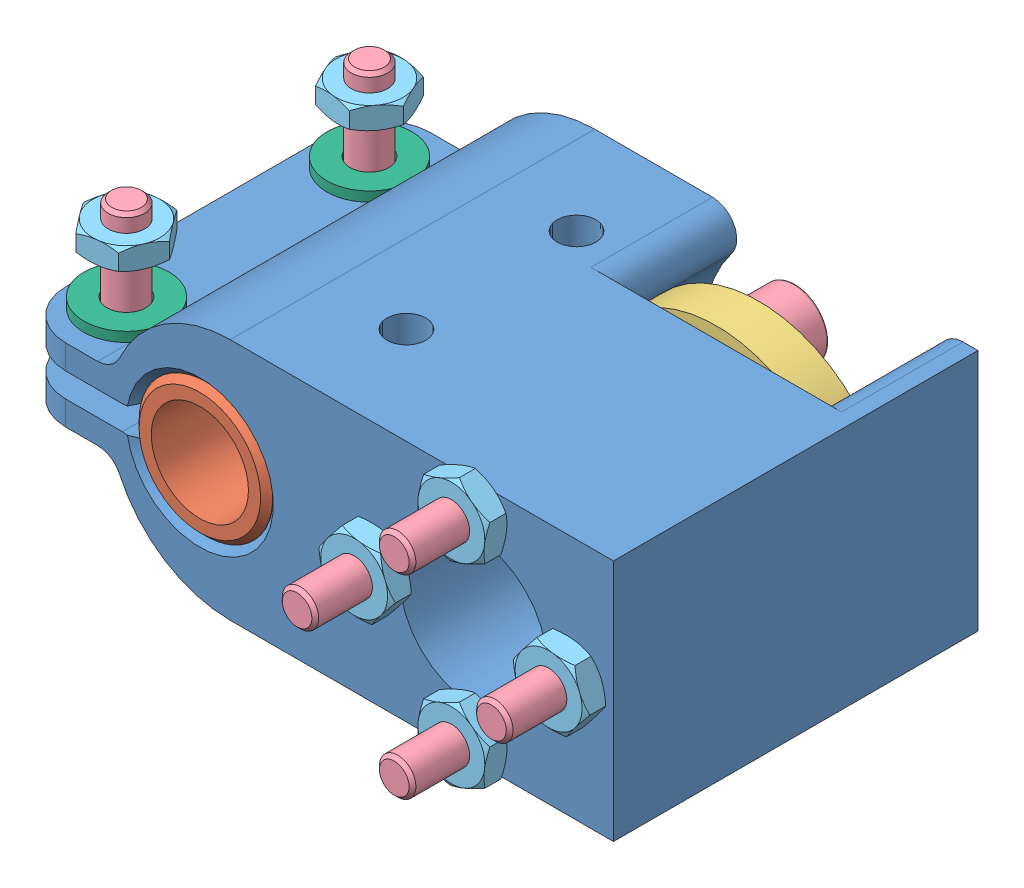
SolidWorks assembly X CHARIOT ASSY, configuration Default. Lengths in mm.
Overall size (49.4 23.51 36.69).
17 component instances, 6 part files, 17 mates.
Components (placement in the parent):
- lead x chariot-1: lead x chariot [Default] at (13.8207 -0.0483 62.5173) size (49.08 20 30.38)
- brass sleeve 30mm-2: brass sleeve 30mm [Default] at (-8.6793 -0.0483 62.5173) x (0.987351 0.158553 0) z (0 0 1) size (11 11 30)
- LeadScrew Nut 8mm x 2mmPitch (1)-1: LeadScrew Nut 8mm x 2mmPitch (1) [Default] at (13.8207 -0.0483 69.0173) x (-1 0 0) z (0 0 -1) size (22 22 16.05)
- socket head cap screw_iso2-2: socket head cap screw_iso2 [ISO 4762 M3 x 30 - 18N] at (5.8207 -0.0483 66.0173) x (0 0 1) z (0.923728 0.383049 0) size (33 5.5 5.5)
- socket head cap screw_iso2-3: socket head cap screw_iso2 [ISO 4762 M3 x 30 - 18N] at (13.8207 7.9517 66.0173) x (0 0 1) z (0.383049 -0.923728 0) size (33 5.5 5.5)
- socket head cap screw_iso2-4: socket head cap screw_iso2 [ISO 4762 M3 x 30 - 18N] at (21.8207 -0.0483 66.0173) x (0 0 1) z (-0.923728 -0.383049 0) size (33 5.5 5.5)
- socket head cap screw_iso2-5: socket head cap screw_iso2 [ISO 4762 M3 x 30 - 18N] at (13.8207 -8.0483 66.0173) x (0 0 1) z (-0.383049 0.923728 0) size (33 5.5 5.5)
- hex thin nut chamfered gradeab_iso-1: hex thin nut chamfered gradeab_iso [ISO - 4035 - M3 - N] at (21.8207 -0.0483 92.5173) x (-0.923728 -0.383049 0) z (0 0 -1) size (5.5 6.35 1.8)
- hex thin nut chamfered gradeab_iso-2: hex thin nut chamfered gradeab_iso [ISO - 4035 - M3 - N] at (13.8207 -8.0483 92.5173) x (-0.383049 0.923728 0) z (0 0 -1) size (5.5 6.35 1.8)
- hex thin nut chamfered gradeab_iso-3: hex thin nut chamfered gradeab_iso [ISO - 4035 - M3 - N] at (5.8207 -0.0483 92.5173) x (0.923728 0.383049 0) z (0 0 -1) size (5.5 6.35 1.8)
- hex thin nut chamfered gradeab_iso-4: hex thin nut chamfered gradeab_iso [ISO - 4035 - M3 - N] at (13.8207 7.9517 92.5173) x (0.383049 -0.923728 0) z (0 0 -1) size (5.5 6.35 1.8)
- socket head cap screw_iso2-8: socket head cap screw_iso2 [ISO 4762 M3 x 10 - 10N] at (-19.7187 -2.2811 67.5173) x (0 1 0) z (0.395734 0 0.918365) size (13 5.5 5.5)
- socket head cap screw_iso2-9: socket head cap screw_iso2 [ISO 4762 M3 x 10 - 10N] at (-19.7187 -2.2811 87.5173) x (0 1 0) z (0.6 0 0.8) size (13 5.5 5.5)
- plain washer 10673 type snl_iso-3: plain washer 10673 type snl_iso [ISO 10673-3.2-S] at (-19.7187 2.9517 67.5173) x (0 1 0) z (0 0 1) size (0.8 7 7)
- plain washer 10673 type snl_iso-4: plain washer 10673 type snl_iso [ISO 10673-3.2-S] at (-19.7187 2.9517 87.5173) x (0 1 0) z (0 0 1) size (0.8 7 7)
- hex thin nut chamfered gradeab_iso-8: hex thin nut chamfered gradeab_iso [ISO - 4035 - M3 - N] at (-19.7187 7.5189 67.5173) x (0.918365 0 -0.395734) z (0 -1 0) size (5.5 6.35 1.8)
- hex thin nut chamfered gradeab_iso-9: hex thin nut chamfered gradeab_iso [ISO - 4035 - M3 - N] at (-19.7187 7.5189 87.5173) x (0.8 0 -0.6) z (0 -1 0) size (5.5 6.35 1.8)
Mates (geometry in assembly coordinates):
- Coincidente2: coincident aligned: plane of lead x chariot-1 through (13.8207 -0.0483 62.5173) normal (0 0 -1); plane of brass sleeve 30mm-2 through (-8.6793 -0.0483 62.5173) normal (0 0 -1)
- Concentrico2: concentric anti-aligned: cylinder of lead x chariot-1 through (-8.6793 -0.0483 62.5163) axis (0 0 1) radius 5.05; cylinder of brass sleeve 30mm-2 through (-8.6793 -0.0483 92.5173) axis (0 0 -1) radius 5.5
- Coincidente5: coincident anti-aligned: plane of lead x chariot-1 through (13.8207 -0.0483 72.5173) normal (0 0 -1); plane of LeadScrew Nut 8mm x 2mmPitch (1)-1 through (13.8207 -0.0483 72.5173) normal (0 0 1)
- Concentrico3: concentric anti-aligned: cylinder of lead x chariot-1 through (13.8207 -0.0483 62.5163) axis (0 0 1) radius 5.05; cylinder of LeadScrew Nut 8mm x 2mmPitch (1)-1 through (13.8207 -0.0483 82.5173) axis (0 0 -1) radius 5.1
- Concentrico4: concentric anti-aligned: cylinder of lead x chariot-1 through (21.8207 -0.0483 62.5163) axis (0 0 1) radius 1.6; cylinder of LeadScrew Nut 8mm x 2mmPitch (1)-1 through (21.8207 -0.0483 72.5173) axis (0 0 -1) radius 1.75
- Concentrico5: concentric anti-aligned: cylinder of lead x chariot-1 through (5.8207 -0.0483 62.5163) axis (0 0 1) radius 1.6; cylinder of socket head cap screw_iso-2 through (5.8207 -0.0483 34.2673) axis (0 0 -1) radius 2.75
- Coincidente7: coincident anti-aligned: plane of LeadScrew Nut 8mm x 2mmPitch (1)-1 through (13.8207 -0.0483 69.0173) normal (0 0 -1); plane of socket head cap screw_iso-2 through (6.8741 -2.5886 69.0173) normal (0 0 1)
- Concentrico8: concentric aligned: cylinder of socket head cap screw_iso-4 through (21.8207 -0.0483 34.2673) axis (0 0 -1) radius 1.5; cylinder of hex thin nut chamfered gradeab_iso-1 through (21.8207 -0.0483 117.5548) axis (0 0 -1) radius 1.5
- Coincidente9: coincident anti-aligned: plane of lead x chariot-1 through (13.8207 -0.0483 92.5173) normal (0 0 1); plane of hex thin nut chamfered gradeab_iso-1 through (20.6043 2.8849 92.5173) normal (0 0 -1)
- Concentrico11: concentric aligned: cylinder of lead x chariot-1 through (-19.7187 9.9527 67.5173) axis (0 -1 0) radius 1.6; cylinder of socket head cap screw_iso-8 through (-19.7187 -34.0311 67.5173) axis (0 -1 0) radius 2.75
- Concentrico12: concentric aligned: cylinder of lead x chariot-1 through (-19.7187 9.9527 87.5173) axis (0 -1 0) radius 1.6; cylinder of socket head cap screw_iso-9 through (-19.7187 -34.0311 87.5173) axis (0 -1 0) radius 2.75
- Concentrico15: concentric aligned: cylinder of lead x chariot-1 through (-19.7187 9.9527 67.5173) axis (0 -1 0) radius 1.6; cylinder of plain washer 10673 type snl_iso-3 through (-19.7187 3.7517 67.5173) axis (0 -1 0) radius 1.6
- Coincidente19: coincident anti-aligned: plane of lead x chariot-1 through (-15.7187 2.9517 52.5173) normal (0 1 0); plane of plain washer 10673 type snl_iso-3 through (-19.7187 2.9517 67.5173) normal (0 -1 0)
- Concentrico16: concentric aligned: cylinder of lead x chariot-1 through (-19.7187 9.9527 87.5173) axis (0 -1 0) radius 1.6; cylinder of plain washer 10673 type snl_iso-4 through (-19.7187 3.7517 87.5173) axis (0 -1 0) radius 1.6
- Coincidente20: coincident anti-aligned: plane of lead x chariot-1 through (-15.7187 2.9517 52.5173) normal (0 1 0); plane of plain washer 10673 type snl_iso-4 through (-19.7187 2.9517 87.5173) normal (0 -1 0)
- Concentrico19: concentric aligned: cylinder of socket head cap screw_iso-8 through (-19.7187 -34.0311 67.5173) axis (0 -1 0) radius 1.5; cylinder of hex thin nut chamfered gradeab_iso-8 through (-19.7187 9.3189 67.5173) axis (0 -1 0) radius 1.25
- Concentrico20: concentric aligned: cylinder of socket head cap screw_iso-9 through (-19.7187 -34.0311 87.5173) axis (0 -1 0) radius 1.5; cylinder of hex thin nut chamfered gradeab_iso-9 through (-19.7187 9.3189 87.5173) axis (0 -1 0) radius 1.25
